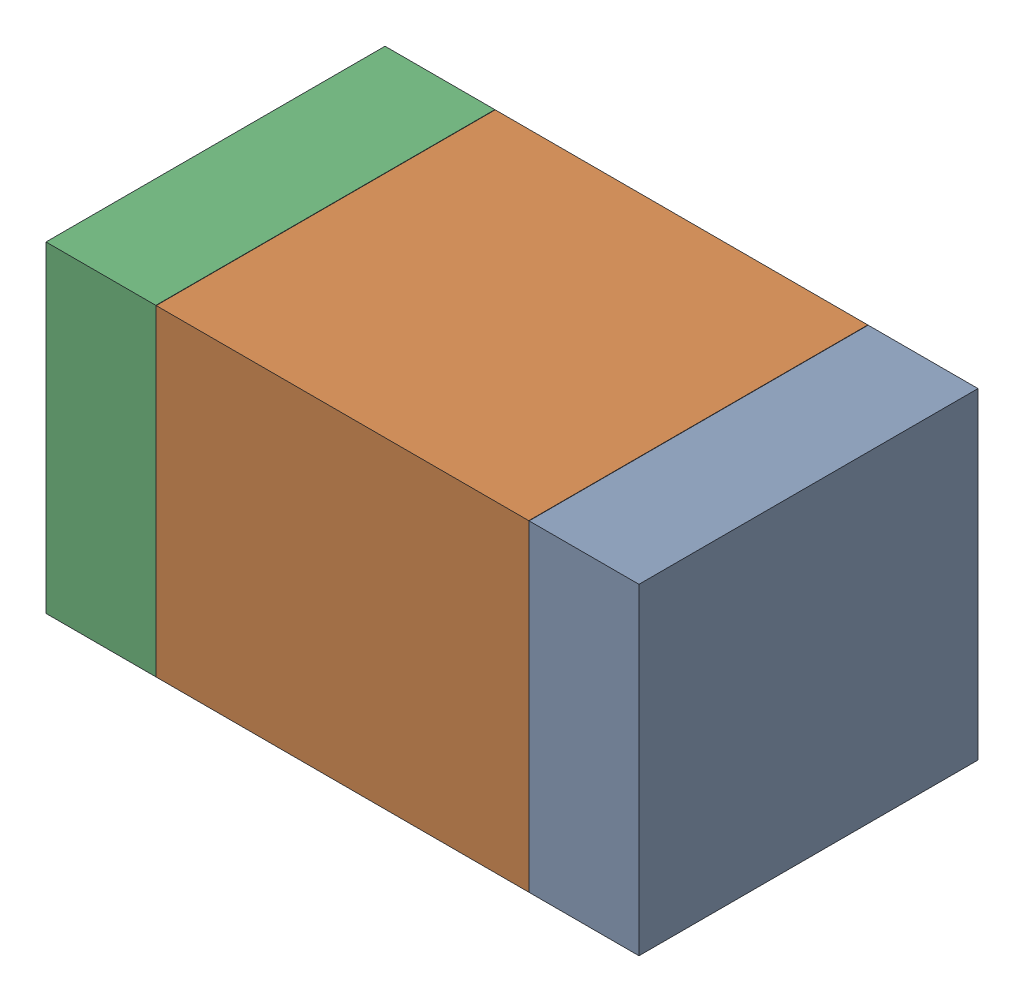
SolidWorks assembly R25, configuration Default. Lengths in mm.
Overall size (1.75 0.95 1).
6 component instances, 2 part files, 0 mates.
Components (placement in the parent):
- 6575498272-1: 6575498272 [Default] at (19.5085 23.876 0) size (0.32 0.95 1)
  - Extruded_8-1: Extruded_8 [Default] at origin size (0.32 0.95 1)
- 6575498112-1: 6575498112 [Default] at (18.796 23.876 0) size (1.1 0.95 1)
  - Extruded_9-1: Extruded_9 [Default] at origin size (1.1 0.95 1)
- 6575498272-2: 6575498272 [Default] at (18.0835 23.876 0) size (0.32 0.95 1)
  - Extruded_8-1: Extruded_8 [Default] at origin size (0.32 0.95 1)
